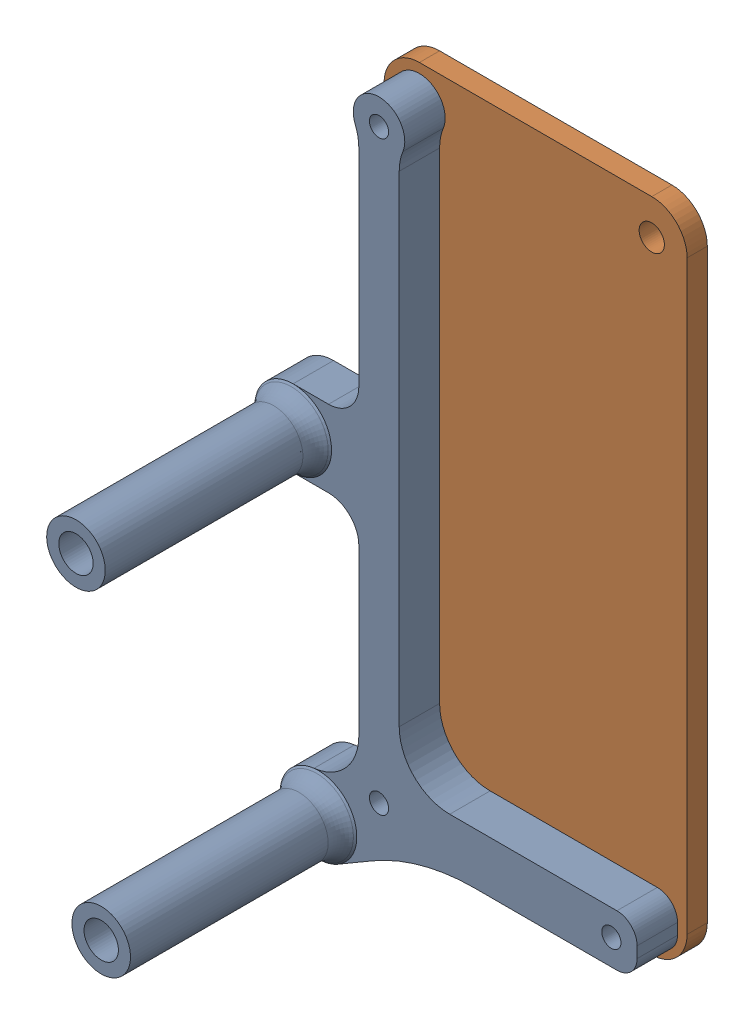
SolidWorks assembly RPi Zero Shelf, configuration Default. Lengths in mm.
Overall size (38.8 69.3 27.5).
2 component instances, 2 part files, 0 mates.
Components (placement in the parent):
- RPi Zero Shelf-1: RPi Zero Shelf [Default] at origin size (37.85 68.35 25.5)
- RPi Zero-1: RPi Zero [Default] at (-83.5 54.0037 25) size (30 65 2)
